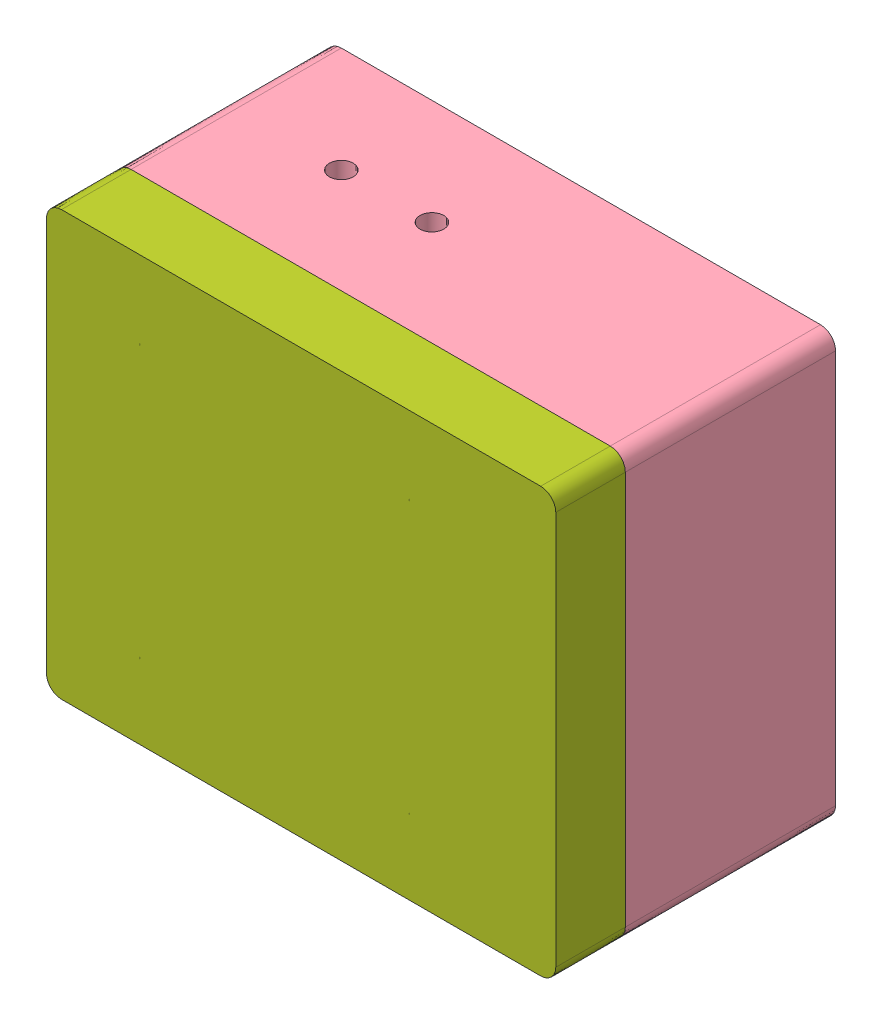
SolidWorks assembly Battery Enclosure 16122020, configuration Default. Lengths in mm.
Overall size (428.6 356.89 235.47).
10 component instances, 7 part files, 27 mates.
Components (placement in the parent):
- GoalZero-2: GoalZero [Default] at (-109.4755 365.738 -45.5585) x (-1 0 0) z (0 1 0) size (285.75 147.32 193.04)
- ACAdapter-1: ACAdapter [Default] at (-158.3705 515.1784 45.3602) x (0 0 -1) z (-1 0 0) size (83.1 32.5 42.8)
- ACAdapter-2: ACAdapter [Default] at (-211.7105 482.6784 45.3602) x (0 0 -1) z (1 0 0) size (83.1 32.5 42.8)
- 8961K107_MOUNTING ADAPTERS FOR DIN RAIL-1: 8961K107_MOUNTING ADAPTERS FOR DIN RAIL [8961K107] at (-109.4755 327.7384 -45.5585) x (0 0 1) z (1 0 0) size (8 51.36 75)
- 8961K107_MOUNTING ADAPTERS FOR DIN RAIL-2: 8961K107_MOUNTING ADAPTERS FOR DIN RAIL [8961K107] at (-109.4755 407.3709 -45.5585) x (0 0 1) z (1 0 0) size (8 51.36 75)
- 1507 Bottom Tub Battery 1-1: 1507 Bottom Tub Battery 1 [Default] at (-109.4755 402.4084 96.5875) x (1 0 0) z (0 -1 0) size (428.6 178.19 356.89)
- 8961K93_MOUNTING ADAPTERS FOR DIN RAIL-2-4: 8961K93_MOUNTING ADAPTERS FOR DIN RAIL-2 [8961K93] at (-287.2755 428.5384 -55.5585) x (0 0 -1) z (1 0 0) size (7.5 35 355.6)
- 8961K93_MOUNTING ADAPTERS FOR DIN RAIL-2-5: 8961K93_MOUNTING ADAPTERS FOR DIN RAIL-2 [8961K93] at (-287.2755 348.9059 -55.5585) x (0 0 -1) z (1 0 0) size (7.5 35 355.6)
- Back_Plate-1: Back_Plate [Default] at (-109.4755 402.4084 -68.2585) x (-1 0 0) z (0 1 0) size (355.6 12.7 254)
- 1507 Top Tub-1: 1507 Top Tub [Default] at (-109.4755 399.895 96.5875) x (-1 0 0) z (0 1 0) size (428.6 59.13 356.89)
Mates (geometry in assembly coordinates):
- Width1: width anti-aligned: plane of GoalZero-2 through (-165.9905 480.1384 -45.5585) normal (1 0 0); plane of GoalZero-2 through (-150.7505 480.1384 -45.5585) normal (-1 0 0); plane of ACAdapter-1 through (-179.7705 482.6784 78.9015) normal (-1 0 0); plane of ACAdapter-1 through (-136.9705 482.6784 78.9015) normal (1 0 0)
- Width2: width anti-aligned: plane of GoalZero-2 through (-204.0905 480.1384 -45.5585) normal (-1 0 0); plane of GoalZero-2 through (-219.3305 480.1384 -45.5585) normal (1 0 0); plane of ACAdapter-2 through (-190.3105 515.1784 78.9015) normal (1 0 0); plane of ACAdapter-2 through (-233.1105 515.1784 78.9015) normal (-1 0 0)
- Coincident4: coincident anti-aligned: plane of GoalZero-2 through (-109.4755 482.6784 -45.5585) normal (0 1 0); plane of ACAdapter-2 through (-211.7105 482.6784 45.3602) normal (0 -1 0)
- Coincident5: coincident anti-aligned: plane of GoalZero-2 through (-109.4755 482.6784 -45.5585) normal (0 1 0); plane of ACAdapter-1 through (-158.3705 482.6784 45.3602) normal (0 -1 0)
- Coincident6: coincident: line of GoalZero-2 through (-236.4755 482.6784 78.9015) axis (1 0 0); plane of ACAdapter-2 through (-233.1105 515.1784 78.9015) normal (0 0 1)
- Coincident7: coincident: line of GoalZero-2 through (-236.4755 482.6784 78.9015) axis (1 0 0); plane of ACAdapter-1 through (-136.9705 482.6784 78.9015) normal (0 0 1)
- Coincident18: coincident anti-aligned: plane of GoalZero-2 through (-109.4755 365.738 -45.5585) normal (0 0 -1); plane of 8961K107_MOUNTING ADAPTERS FOR DIN RAIL-2 through (-109.4755 407.6209 -45.5585) normal (0 0 1)
- Parallel3: parallel anti-aligned: plane of GoalZero-2 through (-109.4755 365.738 -45.5585) normal (0 0 -1); plane of 8961K107_MOUNTING ADAPTERS FOR DIN RAIL-2 through (-109.4755 407.6209 -45.5585) normal (0 0 1)
- Width9: width anti-aligned: plane of 8961K107_MOUNTING ADAPTERS FOR DIN RAIL-1 through (-146.9755 354.0166 -48.4586) normal (-1 0 0); plane of 8961K107_MOUNTING ADAPTERS FOR DIN RAIL-1 through (-71.9755 354.0166 -48.4586) normal (1 0 0); plane of GoalZero-2 through (33.3995 289.6384 101.7615) normal (1 0 0); plane of GoalZero-2 through (-252.3505 289.6384 101.7615) normal (-1 0 0)
- Width10: width anti-aligned: plane of 8961K107_MOUNTING ADAPTERS FOR DIN RAIL-2 through (-71.9755 433.6491 -48.4586) normal (1 0 0); plane of 8961K107_MOUNTING ADAPTERS FOR DIN RAIL-2 through (-146.9755 433.6491 -48.4586) normal (-1 0 0); plane of GoalZero-2 through (-252.3505 289.6384 101.7615) normal (-1 0 0); plane of GoalZero-2 through (33.3995 289.6384 101.7615) normal (1 0 0)
- Width22: width anti-aligned: plane of 8961K93_MOUNTING ADAPTERS FOR DIN RAIL-2-4 through (161.987 415.0384 -55.5585) normal (0 -1 0); plane of 8961K93_MOUNTING ADAPTERS FOR DIN RAIL-2-4 through (161.987 442.0384 -55.5585) normal (0 1 0); plane of 8961K107_MOUNTING ADAPTERS FOR DIN RAIL-2 through (-109.4755 449.7059 -46.5585) normal (0 1 0); plane of 8961K107_MOUNTING ADAPTERS FOR DIN RAIL-2 through (-109.4755 407.3709 -51.9043) normal (0 -1 0)
- Coincident44: coincident anti-aligned: plane of GoalZero-2 through (-109.4755 365.738 -45.5585) normal (0 0 -1); plane of 8961K107_MOUNTING ADAPTERS FOR DIN RAIL-1 through (-109.4755 327.9884 -45.5585) normal (0 0 1)
- Width25: width anti-aligned: plane of 8961K93_MOUNTING ADAPTERS FOR DIN RAIL-2-5 through (161.987 366.4059 -48.0585) normal (0 1 0); plane of 8961K93_MOUNTING ADAPTERS FOR DIN RAIL-2-5 through (161.987 331.4059 -49.0585) normal (0 -1 0); plane of 8961K107_MOUNTING ADAPTERS FOR DIN RAIL-1 through (-109.4755 327.7384 -51.9043) normal (0 -1 0); plane of 8961K107_MOUNTING ADAPTERS FOR DIN RAIL-1 through (-109.4755 370.0734 -46.5585) normal (0 1 0)
- Distance4: distance = 38.1 mm aligned: plane of 8961K107_MOUNTING ADAPTERS FOR DIN RAIL-1 through (-109.4755 327.7384 -51.9043) normal (0 -1 0); plane of GoalZero-2 through (33.3995 289.6384 101.7615) normal (0 -1 0)
- Distance5: distance = 38.1 mm aligned: plane of 8961K93_MOUNTING ADAPTERS FOR DIN RAIL-2-4 through (161.987 442.0384 -55.5585) normal (0 1 0); plane of GoalZero-2 through (33.3995 480.1384 101.7615) normal (0 1 0)
- Coincident56: coincident anti-aligned: plane of 8961K107_MOUNTING ADAPTERS FOR DIN RAIL-1 through (-109.4755 367.3234 -48.0585) normal (0 0 -1); plane of 8961K93_MOUNTING ADAPTERS FOR DIN RAIL-2-5 through (161.987 362.4059 -48.0585) normal (0 0 1)
- Coincident58: coincident anti-aligned: plane of 8961K107_MOUNTING ADAPTERS FOR DIN RAIL-2 through (-109.4755 446.9559 -48.0585) normal (0 0 -1); plane of 8961K93_MOUNTING ADAPTERS FOR DIN RAIL-2-4 through (161.987 415.0384 -48.0585) normal (0 0 1)
- Coincident62: coincident anti-aligned: plane of 1507 Bottom Tub Battery 1-1 through (-245.2687 526.7573 -68.2585) normal (0 0 1); plane of Back_Plate-1 through (-109.4755 402.4084 -68.2585) normal (0 0 -1)
- Width32: width aligned: plane of Back_Plate-1 through (68.3245 275.4084 -55.5585) normal (1 0 0); plane of Back_Plate-1 through (-287.2755 275.4084 -55.5585) normal (-1 0 0); plane of 1507 Bottom Tub Battery 1-1 through (87.9699 402.4084 89.6926) normal (-0.999391 0 0.034899); plane of 1507 Bottom Tub Battery 1-1 through (-306.9209 402.4084 89.6926) normal (0.999391 0 0.034899)
- Width33: width aligned: plane of Back_Plate-1 through (68.3245 529.4084 -55.5585) normal (0 1 0); plane of Back_Plate-1 through (68.3245 275.4084 -55.5585) normal (0 -1 0); plane of 1507 Bottom Tub Battery 1-1 through (-109.4755 551.9824 91.3643) normal (0 -0.999391 0.034899); plane of 1507 Bottom Tub Battery 1-1 through (-109.4755 252.8344 91.3643) normal (0 0.999391 0.034899)
- Coincident63: coincident anti-aligned: plane of 8961K93_MOUNTING ADAPTERS FOR DIN RAIL-2-4 through (161.987 415.0384 -55.5585) normal (0 0 -1); plane of Back_Plate-1 through (-109.4755 402.4084 -55.5585) normal (0 0 1)
- Width34: width anti-aligned: plane of GoalZero-2 through (33.3995 289.6384 101.7615) normal (1 0 0); plane of GoalZero-2 through (-252.3505 289.6384 101.7615) normal (-1 0 0); plane of 1507 Bottom Tub Battery 1-1 through (-306.9209 402.4084 89.6926) normal (0.999391 0 0.034899); plane of 1507 Bottom Tub Battery 1-1 through (87.9699 402.4084 89.6926) normal (-0.999391 0 0.034899)
- Width35: width aligned: plane of ACAdapter-1 through (-158.3705 515.1784 45.3602) normal (0 1 0); plane of GoalZero-2 through (33.3995 289.6384 101.7615) normal (0 -1 0); plane of 1507 Bottom Tub Battery 1-1 through (-109.4755 551.9824 91.3643) normal (0 -0.999391 0.034899); plane of 1507 Bottom Tub Battery 1-1 through (-109.4755 252.8344 91.3643) normal (0 0.999391 0.034899)
- Width36: width aligned: plane of 8961K93_MOUNTING ADAPTERS FOR DIN RAIL-2-5 through (161.987 331.4059 -49.0585) normal (0 -1 0); plane of 8961K93_MOUNTING ADAPTERS FOR DIN RAIL-2-5 through (161.987 366.4059 -48.0585) normal (0 1 0); plane of 8961K107_MOUNTING ADAPTERS FOR DIN RAIL-1 through (-109.4755 327.7384 -51.9043) normal (0 -1 0); plane of 8961K107_MOUNTING ADAPTERS FOR DIN RAIL-1 through (-109.4755 370.0734 -46.5585) normal (0 1 0)
- Width37: width anti-aligned: plane of 8961K93_MOUNTING ADAPTERS FOR DIN RAIL-2-5 through (-287.2755 348.9059 -55.5585) normal (-1 0 0); plane of 8961K93_MOUNTING ADAPTERS FOR DIN RAIL-2-5 through (68.3245 348.9059 -55.5585) normal (1 0 0); plane of 8961K107_MOUNTING ADAPTERS FOR DIN RAIL-1 through (-71.9755 354.0166 -48.4586) normal (1 0 0); plane of 8961K107_MOUNTING ADAPTERS FOR DIN RAIL-1 through (-146.9755 354.0166 -48.4586) normal (-1 0 0)
- Width38: width anti-aligned: plane of 8961K93_MOUNTING ADAPTERS FOR DIN RAIL-2-4 through (-287.2755 428.5384 -55.5585) normal (-1 0 0); plane of 8961K93_MOUNTING ADAPTERS FOR DIN RAIL-2-4 through (68.3245 428.5384 -55.5585) normal (1 0 0); plane of GoalZero-2 through (33.3995 289.6384 101.7615) normal (1 0 0); plane of GoalZero-2 through (-252.3505 289.6384 101.7615) normal (-1 0 0)
- Coincident64: coincident anti-aligned: plane of 1507 Bottom Tub Battery 1-1 through (-109.4755 402.4084 96.5875) normal (0 0 1); plane of 1507 Top Tub-1 through (-109.4755 399.895 96.5875) normal (0 0 -1)
